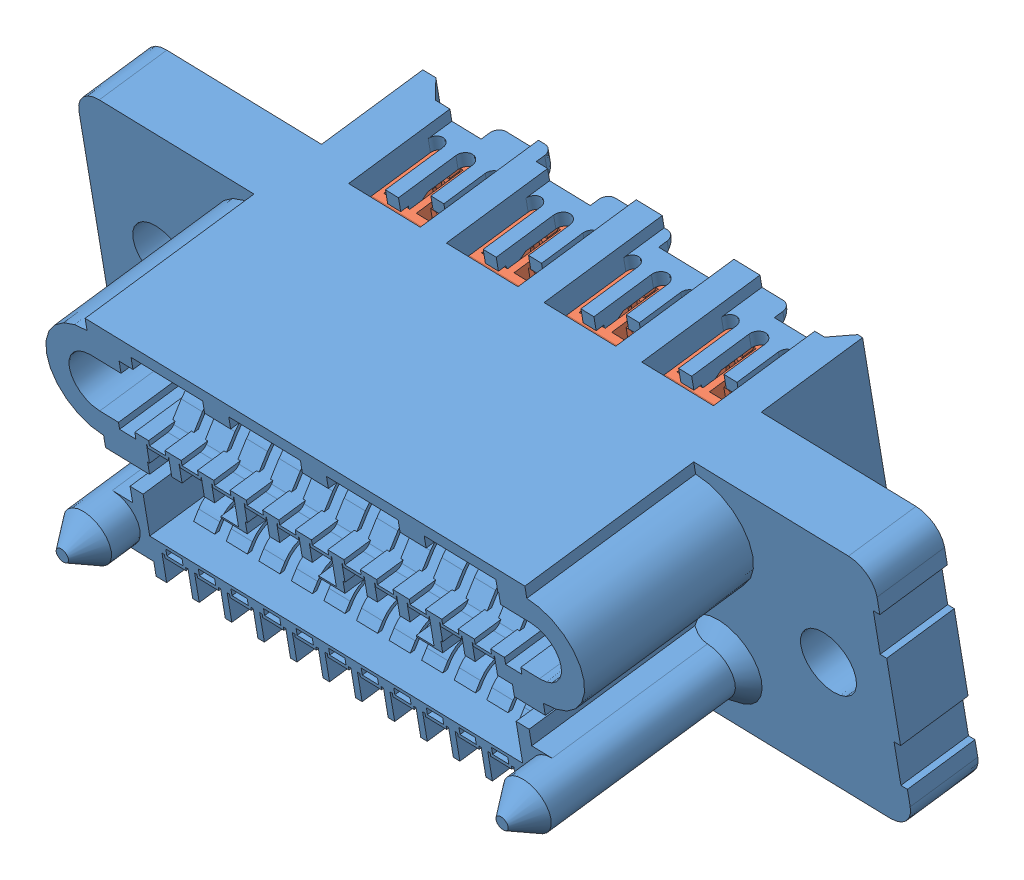
SolidWorks assembly electrical_subassembly, configuration Default. Lengths in mm.
Overall size (49.59 18.69 26.54).
3 component instances, 3 part files, 6 mates.
Components (placement in the parent):
- 292178-1-1: 292178-1 [Default] at (12.8513 -4.7048 116.1081) x (0.999694 -0.002029 0.02466) z (-0.02466 -0.163455 0.986243) size (49 15 23.2)
- 3-173977-1-1: 3-173977-1 [Default] at (13.2338 -1.1246 112.858) x (0.999694 -0.002029 0.02466) z (-0.02466 -0.163455 0.986243) size (23.99 4.6 5.2)
- 1-173977-1-2: 1-173977-1 [Default] at (13.246 -7.0439 111.8773) x (0.999694 -0.002029 0.02466) z (-0.02466 -0.163455 0.986243) size (23.99 4.6 5.2)
Mates (geometry in assembly coordinates):
- Coincident12: coincident anti-aligned: plane of 292178-1-1 through (-11.5627 3.3651 112.9821) normal (0.02466 0.163455 -0.986243); plane of 3-173977-1-1 through (13.2338 -1.1246 112.858) normal (-0.02466 -0.163455 0.986243)
- Concentric16: concentric aligned: cylinder of 292178-1-1 through (2.9419 -1.1037 112.6041) axis (0.02466 0.163455 -0.986243) radius 0.3; cylinder of 3-173977-1-1 through (2.9357 -1.1454 112.8556) axis (0.02466 0.163455 -0.986243) radius 0.35
- Concentric17: concentric aligned: cylinder of 292178-1-1 through (22.9358 -1.1443 113.0973) axis (0.02466 0.163455 -0.986243) radius 0.3; cylinder of 3-173977-1-1 through (22.9295 -1.186 113.3488) axis (0.02466 0.163455 -0.986243) radius 0.35
- Coincident13: coincident anti-aligned: plane of 292178-1-1 through (-11.5627 3.3651 112.9821) normal (0.02466 0.163455 -0.986243); plane of 1-173977-1-2 through (13.246 -7.0439 111.8773) normal (-0.02466 -0.163455 0.986243)
- Concentric20: concentric aligned: cylinder of 292178-1-1 through (2.9541 -7.023 111.6234) axis (0.02466 0.163455 -0.986243) radius 0.3; cylinder of 1-173977-1-2 through (2.9478 -7.0647 111.8749) axis (0.02466 0.163455 -0.986243) radius 0.35
- Concentric21: concentric aligned: cylinder of 292178-1-1 through (22.948 -7.0636 112.1166) axis (0.02466 0.163455 -0.986243) radius 0.3; cylinder of 1-173977-1-2 through (22.9417 -7.1053 112.3681) axis (0.02466 0.163455 -0.986243) radius 0.35
